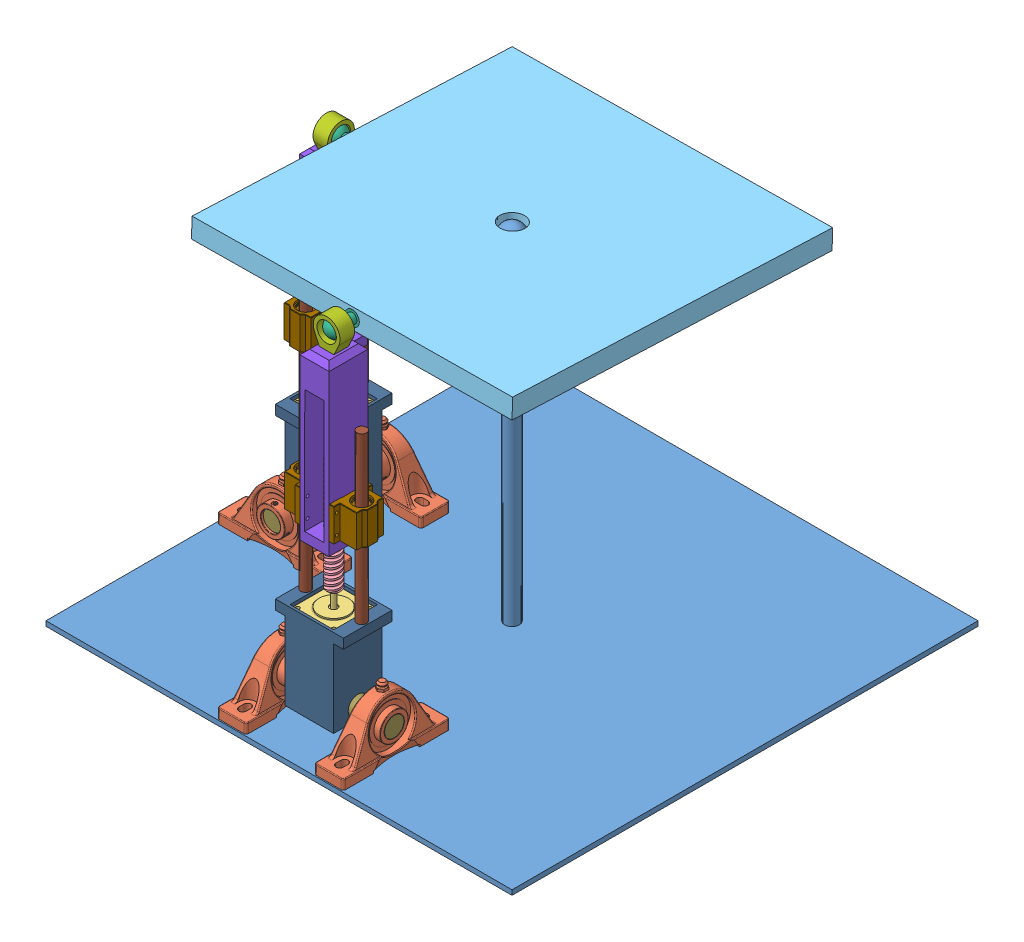
SolidWorks assembly vertical_Assem rev2, configuration Default. Lengths in mm.
Overall size (609.6 472.2 609.6).
28 component instances, 12 part files, 75 mates.
Components (placement in the parent):
- Bottom Platform-1: Bottom Platform [Default] at origin size (609.6 457.83 609.6)
- 7728T560_MOUNTED BALL BEARING WITH CAST IRON HOUSING-1: 7728T560_MOUNTED BALL BEARING WITH CAST IRON HOUSING [7728T56] at (-63.5 42.8625 233.3625) x (0 0 -1) z (1 0 0) size (139.7 80.96 38.1)
- 7728T560_MOUNTED BALL BEARING WITH CAST IRON HOUSING-2: 7728T560_MOUNTED BALL BEARING WITH CAST IRON HOUSING [7728T56] at (-233.3625 42.8625 63.5) size (139.7 80.96 38.1)
- 7728T560_MOUNTED BALL BEARING WITH CAST IRON HOUSING-3: 7728T560_MOUNTED BALL BEARING WITH CAST IRON HOUSING [7728T56] at (-233.3625 42.8625 -63.5) size (139.7 80.96 38.1)
- 7728T560_MOUNTED BALL BEARING WITH CAST IRON HOUSING-4: 7728T560_MOUNTED BALL BEARING WITH CAST IRON HOUSING [7728T56] at (63.5 42.8625 233.3625) x (0 0 1) z (-1 0 0) size (139.7 80.96 38.1)
- 6627T540_POSITION-CONTROL DC MOTOR-2: 6627T540_POSITION-CONTROL DC MOTOR [6627T54] at (0 137.4774 233.2606) x (1 0 0) z (0 0.999999 -0.001077) size (57.15 58.17 99.31)
- 6627T540_POSITION-CONTROL DC MOTOR-3: 6627T540_POSITION-CONTROL DC MOTOR [6627T54] at (-233.3404 137.4775 0) x (0 0 -1) z (0.000234 1 0) size (57.15 58.17 99.31)
- 5966K221_BALL SCREW-3: 5966K221_BALL SCREW [5966K221] at (-233.3356 158.0515 0) x (-0.583927 0.000136 -0.811806) z (-0.000234 -1 0) size (20.38 19.09 157.67)
- 5966K221_BALL SCREW-4: 5966K221_BALL SCREW [5966K221] at (0 158.0514 233.2385) x (0.304775 0.001026 0.952424) z (0 -0.999999 0.001077) size (20.38 19.09 157.67)
- top_Platform-1: top_Platform [Default] at (-0.1644 457.8205 -0.6582) x (-0.999946 -0.01034 0.000572) z (0.000143 0.041462 0.99914) size (419.1 25.4 419.1)
- ball-2: ball [Default] at (-0.009 452.0565 166.7298) x (0.999989 -0.004729 0.000053) z (-0.004728 -0.999129 0.041462) size (25.4 75.77 25.4)
- hole-1: hole [Default] at (0 391.1097 232.9875) x (0 -0.001077 -0.999999) z (1 0 0) size (19.05 81.08 35.03)
- ball-3: ball [Default] at (-167.0289 443.4052 -0.0361) x (-0.008154 0.752081 -0.65902) z (-0.006384 0.658989 0.752125) size (25.4 75.77 25.4)
- hole-2: hole [Default] at (-233.2839 379.1885 0) x (1 -0.000234 0) z (0 0 1) size (19.05 81.08 35.03)
- screw_attach rev2-1: screw_attach rev2 [Default] at (-19.05 217.7274 207.7742) x (1 0 0) z (0 0.001077 0.999999) size (38.1 215.9 50.8)
- 9338T100_MOUNTED LINEAR BALL BRNG-1: 9338T100_MOUNTED LINEAR BALL BRNG [9338T1] at (34.925 255.8547 233.1331) x (0 -0.001077 -0.999999) z (0 0.999999 -0.001077) size (50.8 31.75 42.86)
- 9338T100_MOUNTED LINEAR BALL BRNG-2: 9338T100_MOUNTED LINEAR BALL BRNG [9338T1] at (-34.925 255.8547 233.1331) x (0 0.001077 0.999999) z (0 0.999999 -0.001077) size (50.8 31.75 42.86)
- screw_attach rev2-2: screw_attach rev2 [Default] at (-207.9244 205.8276 -19.05) x (0 0 1) z (-1 0.000234 0) size (38.1 215.9 50.8)
- 9338T100_MOUNTED LINEAR BALL BRNG-3: 9338T100_MOUNTED LINEAR BALL BRNG [9338T1] at (-233.3155 243.9335 -34.925) x (-1 0.000234 0) z (0.000234 1 0) size (50.8 31.75 42.86)
- 9338T100_MOUNTED LINEAR BALL BRNG-4: 9338T100_MOUNTED LINEAR BALL BRNG [9338T1] at (-233.3155 243.9335 34.925) x (1 -0.000234 0) z (0.000234 1 0) size (50.8 31.75 42.86)
- motor mount-2: motor mount [Default] at (-265.1162 26.9949 -31.75) x (0 0 1) z (-1 0.000234 0) size (88.9 114.3 63.5)
- motor mount-3: motor mount [Default] at (-31.75 27.0217 265.1296) x (1 0 0) z (0 0.001077 0.999999) size (88.9 114.3 63.5)
- linear bar-1: linear bar [Default] at (-233.4992 128.5875 -36.5125) x (1 -0.000234 0.000002) z (-0.000002 0 1) size (12.7 228.6 12.7)
- linear bar-2: linear bar [Default] at (36.5125 128.5875 233.2702) x (-0.904178 -0.00046 -0.427157) z (0.427157 -0.000974 -0.904177) size (12.7 228.6 12.7)
- linear bar-3: linear bar [Default] at (-36.5125 128.5876 233.4269) x (-0.912321 -0.000441 -0.409475) z (0.409475 -0.000982 -0.912321) size (12.7 228.6 12.7)
- linear bar-4: linear bar [Default] at (-233.3425 128.5875 36.5125) x (0.952163 -0.000222 0.305589) z (-0.305589 0.000071 0.952163) size (12.7 228.6 12.7)
- horizontal bar-1: horizontal bar [Default] at (-79.375 42.8625 233.3625) size (158.75 25.4 25.4)
- horizontal bar-2: horizontal bar [Default] at (-233.3625 42.8625 -79.375) x (0 0 1) z (-1 0 0) size (158.75 25.4 25.4)
Mates (geometry in assembly coordinates):
- Coincident1: coincident anti-aligned: plane of Bottom Platform-1 through (0 6.35 0) normal (0 1 0); plane of 7728T560_MOUNTED BALL BEARING WITH CAST IRON HOUSING-1 through (-44.45 6.35 203.2) normal (0 -1 0)
- Tangent3: tangent anti-aligned: cylinder of Bottom Platform-1 through (-63.5 6.35 180.975) axis (0 1 0) radius 4.7625; plane of 7728T560_MOUNTED BALL BEARING WITH CAST IRON HOUSING-1 through (-58.7375 6.35 288.925) normal (-1 0 0)
- Tangent5: tangent anti-aligned: cylinder of Bottom Platform-1 through (-63.5 6.35 285.75) axis (0 1 0) radius 4.7625; plane of 7728T560_MOUNTED BALL BEARING WITH CAST IRON HOUSING-1 through (-58.7375 6.35 288.925) normal (-1 0 0)
- Coincident3: coincident: cylinder of Bottom Platform-1 through (-63.5 6.35 180.975) axis (0 1 0) radius 4.7625; moEndPointRef_w of 7728T560_MOUNTED BALL BEARING WITH CAST IRON HOUSING-1
- Coincident4: coincident anti-aligned: plane of Bottom Platform-1 through (0 6.35 0) normal (0 1 0); plane of 7728T560_MOUNTED BALL BEARING WITH CAST IRON HOUSING-2 through (-303.2125 6.35 82.55) normal (0 -1 0)
- Coincident5: coincident anti-aligned: plane of Bottom Platform-1 through (0 6.35 0) normal (0 1 0); plane of 7728T560_MOUNTED BALL BEARING WITH CAST IRON HOUSING-4 through (44.45 6.35 163.5125) normal (0 -1 0)
- Coincident6: coincident anti-aligned: plane of Bottom Platform-1 through (0 6.35 0) normal (0 1 0); plane of 7728T560_MOUNTED BALL BEARING WITH CAST IRON HOUSING-3 through (-303.2125 6.35 -44.45) normal (0 -1 0)
- Tangent6: tangent anti-aligned: cylinder of Bottom Platform-1 through (63.5 6.35 285.75) axis (0 1 0) radius 4.7625; plane of 7728T560_MOUNTED BALL BEARING WITH CAST IRON HOUSING-4 through (68.2625 6.35 282.575) normal (-1 0 0)
- Tangent7: tangent anti-aligned: cylinder of Bottom Platform-1 through (63.5 6.35 180.975) axis (0 1 0) radius 4.7625; plane of 7728T560_MOUNTED BALL BEARING WITH CAST IRON HOUSING-4 through (68.2625 6.35 177.8) normal (-1 0 0)
- Coincident7: coincident: cylinder of Bottom Platform-1 through (63.5 6.35 180.975) axis (0 1 0) radius 4.7625; moEndPointRef_w of 7728T560_MOUNTED BALL BEARING WITH CAST IRON HOUSING-4
- Tangent8: tangent anti-aligned: cylinder of Bottom Platform-1 through (-180.975 6.35 63.5) axis (0 1 0) radius 4.7625; plane of 7728T560_MOUNTED BALL BEARING WITH CAST IRON HOUSING-2 through (-184.15 6.35 58.7375) normal (0 0 1)
- Tangent9: tangent anti-aligned: cylinder of Bottom Platform-1 through (-285.75 6.35 63.5) axis (0 1 0) radius 4.7625; plane of 7728T560_MOUNTED BALL BEARING WITH CAST IRON HOUSING-2 through (-288.925 6.35 58.7375) normal (0 0 1)
- Coincident8: coincident: cylinder of Bottom Platform-1 through (-180.975 6.35 63.5) axis (0 1 0) radius 4.7625; moEndPointRef_w of 7728T560_MOUNTED BALL BEARING WITH CAST IRON HOUSING-2
- Tangent10: tangent anti-aligned: cylinder of Bottom Platform-1 through (-180.975 6.35 -63.5) axis (0 1 0) radius 4.7625; plane of 7728T560_MOUNTED BALL BEARING WITH CAST IRON HOUSING-3 through (-184.15 6.35 -68.2625) normal (0 0 1)
- Tangent11: tangent anti-aligned: cylinder of Bottom Platform-1 through (-285.75 6.35 -63.5) axis (0 1 0) radius 4.7625; plane of 7728T560_MOUNTED BALL BEARING WITH CAST IRON HOUSING-3 through (-288.925 6.35 -68.2625) normal (0 0 1)
- Coincident9: coincident: cylinder of Bottom Platform-1 through (-285.75 6.35 -63.5) axis (0 1 0) radius 4.7625; moEndPointRef_w of 7728T560_MOUNTED BALL BEARING WITH CAST IRON HOUSING-3
- Coincident12: coincident: moEndPointRef_w of 6627T540_POSITION-CONTROL DC MOTOR-3; plane of assembly
- Coincident13: coincident: moEndPointRef_w of 6627T540_POSITION-CONTROL DC MOTOR-2; plane of assembly
- Coincident16: coincident anti-aligned: plane of 6627T540_POSITION-CONTROL DC MOTOR-3 through (-236.5106 158.0522 0) normal (0.000234 1 0); plane of 5966K221_BALL SCREW-3 through (-233.3356 158.0515 0) normal (-0.000234 -1 0)
- Concentric5: concentric anti-aligned: cylinder of 6627T540_POSITION-CONTROL DC MOTOR-3 through (-233.3356 158.0515 0) axis (0.000234 1 0) radius 3.175; cylinder of 5966K221_BALL SCREW-3 through (-233.3 310.4515 0) axis (-0.000234 -1 0) radius 9.525
- Concentric6: concentric anti-aligned: cylinder of 6627T540_POSITION-CONTROL DC MOTOR-2 through (0 158.0514 233.2385) axis (0 0.999999 -0.001077) radius 3.175; cylinder of 5966K221_BALL SCREW-4 through (0 310.4513 233.0743) axis (0 -0.999999 0.001077) radius 9.525
- Coincident17: coincident anti-aligned: plane of 6627T540_POSITION-CONTROL DC MOTOR-2 through (0 158.048 230.0635) normal (0 0.999999 -0.001077); plane of 5966K221_BALL SCREW-4 through (0 158.0514 233.2385) normal (0 -0.999999 0.001077)
- Concentric18: concentric anti-aligned: cylinder of top_Platform-1 through (-0.0029 453.8205 209.2382) axis (0.000143 0.041462 0.99914) radius 9.525; cylinder of ball-2 through (-0.0029 453.8205 209.2382) axis (-0.000143 -0.041462 -0.99914) radius 9.525
- Coincident31: coincident aligned: circle of top_Platform-1; circle of ball-2
- Tangent12: tangent aligned: sphere of ball-2; cylinder of hole-1 through (0 454.6851 242.444) axis (0 -0.001077 -0.999999) radius 12.7
- Concentric20: concentric anti-aligned: cylinder of top_Platform-1 through (-209.5716 442.9653 -0.0117) axis (-0.999946 -0.01034 0.000572) radius 9.525; cylinder of ball-3 through (-209.5716 442.9653 -0.0117) axis (0.999946 0.01034 -0.000572) radius 9.525
- Coincident35: coincident aligned: plane of top_Platform-1 through (-209.4102 438.9653 209.8846) normal (-0.999946 -0.01034 0.000572); plane of ball-3 through (-209.5716 442.9653 -0.0117) normal (-0.999946 -0.01034 0.000572)
- Tangent13: tangent aligned: sphere of ball-3; cylinder of hole-2 through (-242.7941 442.756 0) axis (1 -0.000234 0) radius 12.7
- Tangent14: tangent aligned: sphere of ball-2; plane of hole-1 through (0 454.6851 242.444) normal (0 0.001077 0.999999)
- Tangent15: tangent aligned: sphere of ball-3; plane of hole-2 through (-242.7941 442.756 0) normal (-1 0.000234 0)
- Parallel5: parallel anti-aligned: plane of Bottom Platform-1 through (0 6.35 0) normal (0 1 0); plane of top_Platform-1
- Tangent16: tangent aligned: sphere of Bottom Platform-1; cylinder of top_Platform-1 through (0.0986 432.4437 0.3949) axis (-0.010355 0.999087 -0.041459) radius 15.875
- Tangent18: tangent aligned: sphere of Bottom Platform-1; plane of top_Platform-1 through (-0.1644 457.8205 -0.6582) normal (-0.010355 0.999087 -0.041459)
- Concentric21: concentric anti-aligned: cylinder of hole-1 through (0 433.6546 232.9417) axis (0 -0.999999 0.001077) radius 9.525; cylinder of screw_attach rev2-1 through (0 433.6546 232.9417) axis (0 0.999999 -0.001077) radius 9.525
- Screw1: screw = 25.4 mm aligned: cylinder of 5966K221_BALL SCREW-4 through (0 310.4513 233.0743) axis (0 -0.999999 0.001077) radius 9.525; cylinder of screw_attach rev2-1 through (0 217.7548 233.1742) axis (0 -0.999999 0.001077) radius 9.525
- Parallel6: parallel aligned: plane of hole-1 through (0 454.6851 242.444) normal (0 0.001077 0.999999); plane of screw_attach rev2-1 through (-19.05 217.7821 258.5742) normal (0 0.001077 0.999999)
- Coincident38: coincident anti-aligned: plane of hole-1 through (9.525 433.6649 242.4667) normal (0 -0.999999 0.001077); plane of screw_attach rev2-1 through (-19.05 433.682 258.3417) normal (0 0.999999 -0.001077)
- Coincident39: coincident anti-aligned: plane of screw_attach rev2-1 through (19.05 217.7821 258.5742) normal (1 0 0); plane of 9338T100_MOUNTED LINEAR BALL BRNG-1 through (19.05 277.2586 207.7101) normal (-1 0 0)
- Concentric23: concentric anti-aligned: cylinder of screw_attach rev2-1 through (19.05 268.5317 211.6882) axis (1 0 0) radius 1.9844; cylinder of 9338T100_MOUNTED LINEAR BALL BRNG-1 through (31.0127 268.5317 211.6882) axis (-1 0 0) radius 1.9844
- Concentric24: concentric anti-aligned: cylinder of screw_attach rev2-1 through (19.05 268.5778 254.5507) axis (1 0 0) radius 1.9844; cylinder of 9338T100_MOUNTED LINEAR BALL BRNG-1 through (31.0127 268.5778 254.5507) axis (-1 0 0) radius 1.9844
- Coincident40: coincident anti-aligned: plane of screw_attach rev2-1 through (-19.05 217.7821 258.5742) normal (-1 0 0); plane of 9338T100_MOUNTED LINEAR BALL BRNG-2 through (-19.05 277.2586 207.7101) normal (1 0 0)
- Concentric25: concentric anti-aligned: cylinder of screw_attach rev2-1 through (-19.05 268.5778 254.5507) axis (-1 0 0) radius 1.9844; cylinder of 9338T100_MOUNTED LINEAR BALL BRNG-2 through (-31.0127 268.5778 254.5507) axis (1 0 0) radius 1.9844
- Concentric26: concentric anti-aligned: cylinder of screw_attach rev2-1 through (-19.05 268.5317 211.6882) axis (-1 0 0) radius 1.9844; cylinder of 9338T100_MOUNTED LINEAR BALL BRNG-2 through (-31.0127 268.5317 211.6882) axis (1 0 0) radius 1.9844
- Screw4: screw = 25.4 mm aligned: cylinder of 5966K221_BALL SCREW-3 through (-233.3 310.4515 0) axis (-0.000234 -1 0) radius 9.525; cylinder of screw_attach rev2-2 through (-233.3244 205.8335 0) axis (-0.000234 -1 0) radius 9.525
- Concentric31: concentric anti-aligned: cylinder of hole-2 through (-233.274 421.7335 0) axis (-0.000234 -1 0) radius 9.525; cylinder of screw_attach rev2-2 through (-233.274 421.7335 0) axis (0.000234 1 0) radius 9.525
- Coincident46: coincident anti-aligned: plane of hole-2 through (-242.799 421.7357 9.525) normal (-0.000234 -1 0); plane of screw_attach rev2-2 through (-258.674 421.7395 -19.05) normal (0.000234 1 0)
- Coincident47: coincident anti-aligned: plane of screw_attach rev2-2 through (-258.7244 205.8395 -19.05) normal (0 0 -1); plane of 9338T100_MOUNTED LINEAR BALL BRNG-3 through (-258.7105 265.3707 -19.05) normal (0 0 1)
- Concentric32: concentric anti-aligned: cylinder of screw_attach rev2-2 through (-211.8813 256.6285 -19.05) axis (0 0 -1) radius 1.9844; cylinder of 9338T100_MOUNTED LINEAR BALL BRNG-3 through (-211.8813 256.6285 -31.0127) axis (0 0 1) radius 1.9844
- Concentric33: concentric anti-aligned: cylinder of screw_attach rev2-2 through (-254.7438 256.6385 -19.05) axis (0 0 -1) radius 1.9844; cylinder of 9338T100_MOUNTED LINEAR BALL BRNG-3 through (-254.7438 256.6385 -31.0127) axis (0 0 1) radius 1.9844
- Coincident48: coincident anti-aligned: plane of screw_attach rev2-2 through (-258.7244 205.8395 19.05) normal (0 0 1); plane of 9338T100_MOUNTED LINEAR BALL BRNG-4 through (-258.7105 265.3707 19.05) normal (0 0 -1)
- Concentric34: concentric anti-aligned: cylinder of screw_attach rev2-2 through (-254.7438 256.6385 19.05) axis (0 0 1) radius 1.9844; cylinder of 9338T100_MOUNTED LINEAR BALL BRNG-4 through (-254.7438 256.6385 31.0127) axis (0 0 -1) radius 1.9844
- Concentric35: concentric anti-aligned: cylinder of screw_attach rev2-2 through (-211.8813 256.6285 19.05) axis (0 0 1) radius 1.9844; cylinder of 9338T100_MOUNTED LINEAR BALL BRNG-4 through (-211.8813 256.6285 31.0127) axis (0 0 -1) radius 1.9844
- Parallel10: parallel aligned: plane of hole-2 through (-242.7941 442.756 0) normal (-1 0.000234 0); plane of screw_attach rev2-2 through (-258.7244 205.8395 -19.05) normal (-1 0.000234 0)
- Coincident50: coincident anti-aligned: plane of 6627T540_POSITION-CONTROL DC MOTOR-3 through (-218.2712 58.734 25.019) normal (-0.000234 -1 0); plane of motor mount-2 through (-265.1088 58.7449 -31.75) normal (0.000234 1 0)
- Coincident51: coincident anti-aligned: plane of 6627T540_POSITION-CONTROL DC MOTOR-3 through (-207.9416 132.3916 -28.575) normal (0 0 -1); plane of motor mount-2 through (-261.9145 141.2942 -28.575) normal (0 0 1)
- Coincident52: coincident anti-aligned: plane of 6627T540_POSITION-CONTROL DC MOTOR-3 through (-261.9166 132.4042 -25.4) normal (-1 0.000234 0); plane of motor mount-2 through (-261.9145 141.2942 -28.575) normal (1 -0.000234 0)
- Coincident53: coincident anti-aligned: plane of 6627T540_POSITION-CONTROL DC MOTOR-2 through (-25.019 58.7537 248.433) normal (0 -0.999999 0.001077); plane of motor mount-3 through (-31.75 58.7717 265.0954) normal (0 0.999999 -0.001077)
- Coincident54: coincident anti-aligned: plane of 6627T540_POSITION-CONTROL DC MOTOR-2 through (25.4 132.3667 204.6911) normal (0 -0.001077 -0.999999); plane of motor mount-3 through (-28.575 141.2567 204.6815) normal (0 0.001077 0.999999)
- Coincident55: coincident anti-aligned: plane of 6627T540_POSITION-CONTROL DC MOTOR-2 through (28.575 132.4248 258.6661) normal (1 0 0); plane of motor mount-3 through (28.575 141.3182 261.8315) normal (-1 0 0)
- Coincident56: coincident aligned: plane of motor mount-2 through (-265.0925 128.5949 -44.45) normal (-0.000234 -1 0); plane of linear bar-1 through (-233.4992 128.5875 -36.5125) normal (-0.000234 -1 0)
- Concentric43: concentric anti-aligned: cylinder of motor mount-2 through (-233.4962 141.2875 -36.5125) axis (0.000234 1 0) radius 6.35; cylinder of linear bar-1 through (-233.4458 357.1875 -36.5125) axis (-0.000234 -1 0) radius 6.35
- Concentric44: concentric anti-aligned: cylinder of motor mount-2 through (-233.3395 141.2875 36.5125) axis (0.000234 1 0) radius 6.35; cylinder of linear bar-4 through (-233.2891 357.1875 36.5125) axis (-0.000234 -1 0) radius 6.35
- Coincident57: coincident aligned: plane of motor mount-2 through (-265.0925 128.5949 44.45) normal (-0.000234 -1 0); plane of linear bar-4 through (-233.3425 128.5875 36.5125) normal (-0.000234 -1 0)
- Concentric45: concentric anti-aligned: cylinder of motor mount-3 through (-36.5125 141.2876 233.4132) axis (0 0.999999 -0.001077) radius 6.35; cylinder of linear bar-3 through (-36.5125 357.1875 233.1807) axis (0 -0.999999 0.001077) radius 6.35
- Concentric46: concentric anti-aligned: cylinder of motor mount-3 through (36.5125 141.2874 233.2565) axis (0 0.999999 -0.001077) radius 6.35; cylinder of linear bar-2 through (36.5125 357.1873 233.024) axis (0 -0.999999 0.001077) radius 6.35
- Coincident58: coincident aligned: plane of motor mount-3 through (-44.45 128.6216 265.0202) normal (0 -0.999999 0.001077); plane of linear bar-3 through (-36.5125 128.5876 233.4269) normal (0 -0.999999 0.001077)
- Coincident59: coincident aligned: plane of motor mount-3 through (44.45 128.6216 265.0202) normal (0 -0.999999 0.001077); plane of linear bar-2 through (36.5125 128.5875 233.2702) normal (0 -0.999999 0.001077)
- Concentric47: concentric anti-aligned: cylinder of 9338T100_MOUNTED LINEAR BALL BRNG-1 through (36.5125 234.4235 233.1562) axis (0 0.999999 -0.001077) radius 6.35; cylinder of linear bar-2 through (36.5125 357.1873 233.024) axis (0 -0.999999 0.001077) radius 6.35
- Concentric48: concentric anti-aligned: cylinder of 9338T100_MOUNTED LINEAR BALL BRNG-4 through (-233.3205 222.5023 36.5125) axis (0.000234 1 0) radius 6.35; cylinder of linear bar-4 through (-233.2891 357.1875 36.5125) axis (-0.000234 -1 0) radius 6.35
- Coincident60: coincident aligned: plane of 7728T560_MOUNTED BALL BEARING WITH CAST IRON HOUSING-1 through (-79.375 42.8625 233.3625) normal (-1 0 0); plane of horizontal bar-1 through (-79.375 42.8625 233.3625) normal (-1 0 0)
- Concentric51: concentric anti-aligned: cylinder of 7728T560_MOUNTED BALL BEARING WITH CAST IRON HOUSING-1 through (-79.375 42.8625 233.3625) axis (1 0 0) radius 12.7025; cylinder of horizontal bar-1 through (79.375 42.8625 233.3625) axis (-1 0 0) radius 12.7
- Coincident61: coincident aligned: plane of 7728T560_MOUNTED BALL BEARING WITH CAST IRON HOUSING-3 through (-233.3625 42.8625 -79.375) normal (0 0 -1); plane of horizontal bar-2 through (-233.3625 42.8625 -79.375) normal (0 0 -1)
- Concentric52: concentric anti-aligned: cylinder of 7728T560_MOUNTED BALL BEARING WITH CAST IRON HOUSING-3 through (-233.3625 42.8625 -79.375) axis (0 0 1) radius 12.7025; cylinder of horizontal bar-2 through (-233.3625 42.8625 79.375) axis (0 0 -1) radius 12.7
- Concentric54: concentric anti-aligned: cylinder of motor mount-2 through (-233.3625 42.8625 31.75) axis (0 0 1) radius 12.7; cylinder of horizontal bar-2 through (-233.3625 42.8625 79.375) axis (0 0 -1) radius 12.7
- Concentric56: concentric anti-aligned: cylinder of motor mount-3 through (31.75 42.8625 233.3625) axis (1 0 0) radius 12.7; cylinder of horizontal bar-1 through (79.375 42.8625 233.3625) axis (-1 0 0) radius 12.7
